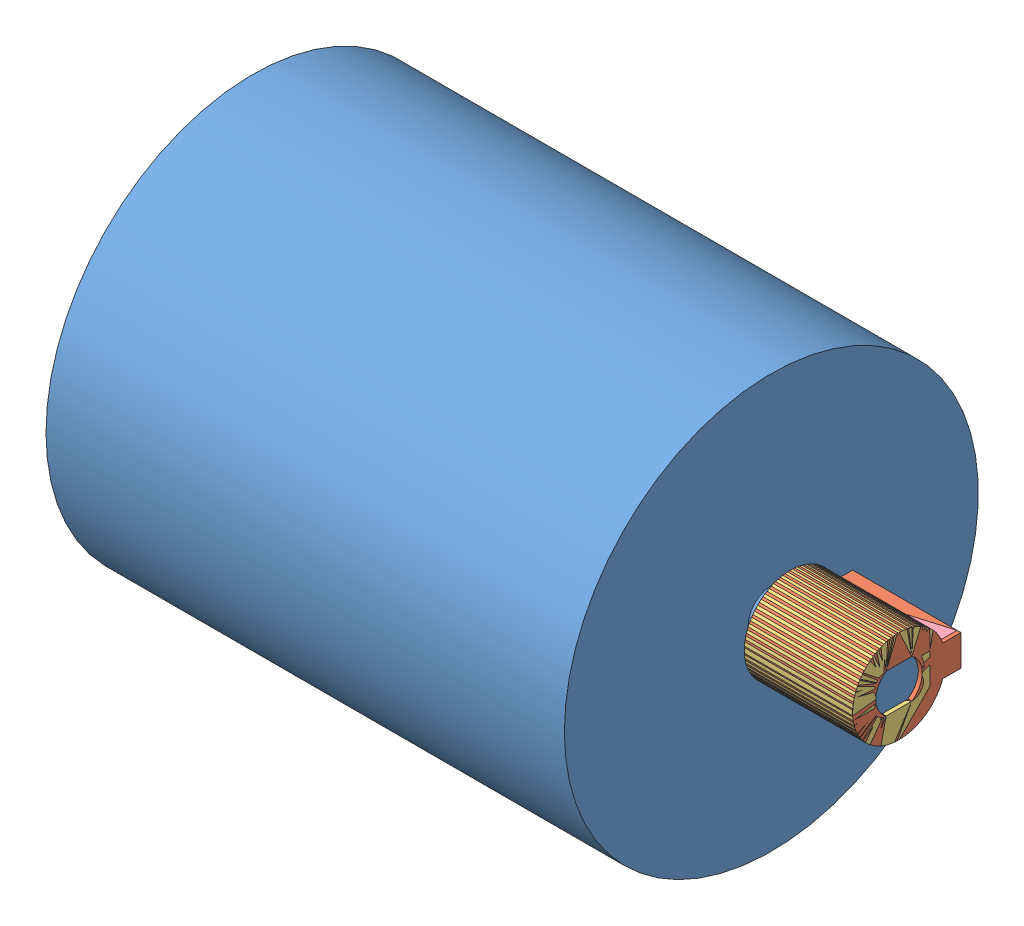
SolidWorks assembly ТП.016.08.00 - Электромотор в сборе, configuration Вар 02. Lengths in mm.
Overall size (167 107 107).
6 component instances, 4 part files, 6 mates.
Components (placement in the parent):
- Двигатель малый BDLC-1: Двигатель малый BDLC [Без лап] at origin size (166 107 107)
- ТП.016.08.01 - Втулка двигателя малого-1: ТП.016.08.01 - Втулка двигателя малого [--] at (32 0 0) x (0 0 1) z (-1 0 0) size (28 24 28) (hidden)
- ТП.016.08.01.00 - Втулка двигателя малого(СБ)-1: ТП.016.08.01.00 - Втулка двигателя малого(СБ) [00] at (32 0 0) x (0 0 1) z (-1 0 0) size (28 24 28)
  - ТП.016.08.01 - Втулка двигателя малого-1: ТП.016.08.01 - Втулка двигателя малого [--] at origin size (28 24 28) (hidden)
  - ТП.016.08.01.01 - Втулка двигателя малого (тело)-1: ТП.016.08.01.01 - Втулка двигателя малого (тело) [--] at origin size (23.31 24 28)
  - ТП.016.08.01.02 - Шпонка 8х8х28-1: ТП.016.08.01.02 - Шпонка 8х8х28 [--] at origin size (8 8 27)
Mates (geometry in assembly coordinates):
- Совпадение1: coincident: plane of Двигатель малый BDLC-1 through (32 0 0) normal (1 0 0); plane of ТП.016.08.01 - Втулка двигателя малого-1 through (32 0 0) normal (-1 0 0)
- Совпадение2: coincident: plane of ТП.016.08.01 - Втулка двигателя малого-1 through (32 0 0) normal (0 1 0); plane of assembly through (0 0 0) normal (0 1 0)
- Совпадение3: coincident: plane of ТП.016.08.01 - Втулка двигателя малого-1 through (32 0 0) normal (0 0 1); plane of assembly through (0 0 0) normal (0 0 1)
- Совпадение4: coincident: plane of ТП.016.08.01 - Втулка двигателя малого-1 through (33 0 0) normal (1 0 0); plane of ТП.016.08.01.00 - Втулка двигателя малого(СБ)-1/ТП.016.08.01.01 - Втулка двигателя малого (тело)-1 through (33 0 0) normal (1 0 0)
- Концентричный1: concentric: cylinder of ТП.016.08.01 - Втулка двигателя малого-1 through (33 0 0) axis (-1 0 0) radius 12; cylinder of ТП.016.08.01.00 - Втулка двигателя малого(СБ)-1/ТП.016.08.01.01 - Втулка двигателя малого (тело)-1 through (-28.4594 0 0) axis (1 0 0) radius 12
- Совпадение5: coincident: plane of ТП.016.08.01 - Втулка двигателя малого-1 through (33 4 -11.3137) normal (0 1 0); plane of ТП.016.08.01.00 - Втулка двигателя малого(СБ)-1/ТП.016.08.01.02 - Шпонка 8х8х28-1 through (-6.3137 4 -8) normal (0 1 0)
